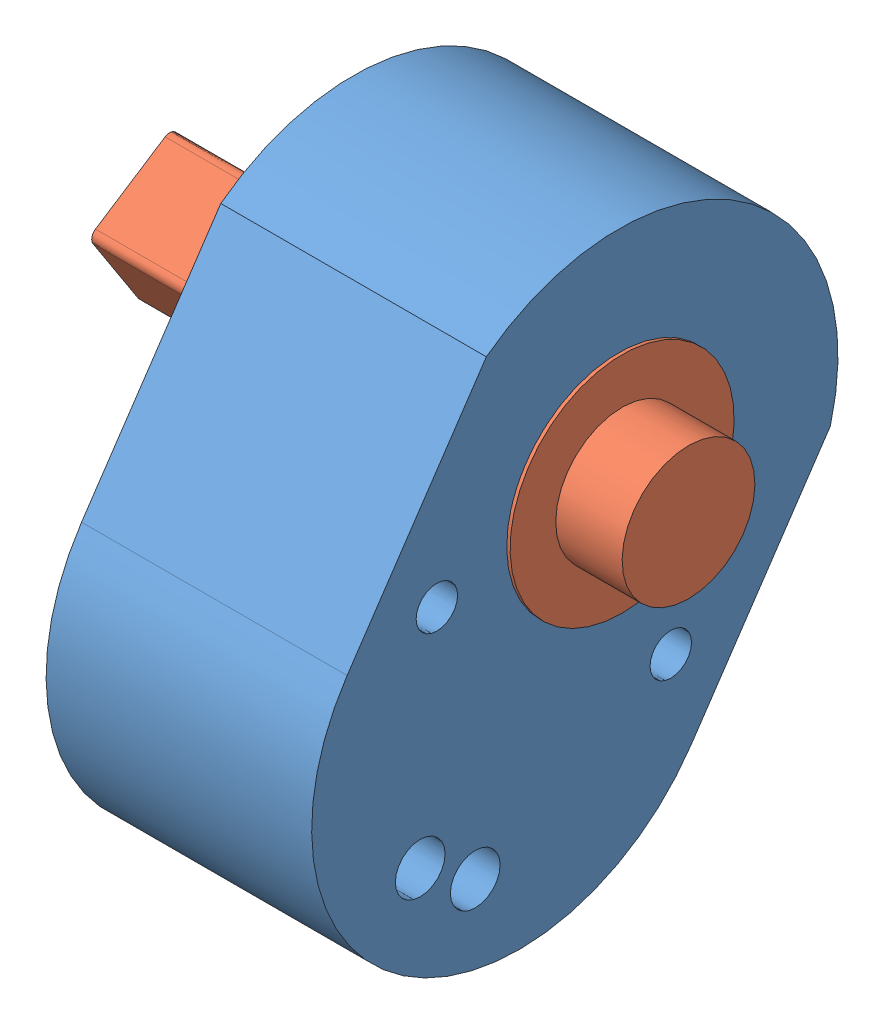
SolidWorks assembly 装配体棘轮, configuration 默认. Lengths in mm.
Overall size (32 34.61 31.71).
6 component instances, 6 part files, 7 mates.
Components (placement in the parent):
- 棘轮-1: 棘轮 [默认] at origin size (16 34.61 31.71)
- 棘轮轮齿-1: 棘轮轮齿 [默认] at (1.5 44.1826 -31.5548) x (0 -0.543538 0.839384) z (0 0.839384 0.543538) size (18.39 32 18.39)
- 棘轮顶片-1: 棘轮顶片 [默认] at (13.5 27.7832 -22.9057) x (0 -0.221935 0.975062) z (-1 0 0) size (11.37 7.28 8)
- 零件2^装配体棘轮-1: 零件2^装配体棘轮 [默认] at origin (virtual)
- 零件3^装配体棘轮-1: 零件3^装配体棘轮 [默认] at origin (virtual)
- 棘轮壳片-1: 棘轮壳片 [默认] at (3.5 44.1826 -31.5548) x (0 0 1) z (0 -1 0) size (27.54 2 29.93)
Mates (geometry in assembly coordinates):
- 同心1: concentric anti-aligned: cylinder of 棘轮-1 through (17.3 44.1826 -31.5548) axis (-1 0 0) radius 6.75; cylinder of 棘轮轮齿-1 through (21.5 44.1826 -31.5548) axis (1 0 0) radius 6.75
- 同心2: concentric anti-aligned: cylinder of 棘轮-1 through (17.3 27.7832 -22.9057) axis (-1 0 0) radius 1.5; cylinder of 棘轮顶片-1 through (5.5 27.7832 -22.9057) axis (1 0 0) radius 1.4
- 重合1: coincident anti-aligned: plane of 棘轮-1 through (13.5 40.5189 -29.0836) normal (-1 0 0); plane of 棘轮顶片-1 through (13.5 27.5773 -25.2969) normal (1 0 0)
- 重合2: coincident anti-aligned: plane of 棘轮-1 through (13.5 40.5189 -29.0836) normal (-1 0 0); plane of 棘轮轮齿-1 through (13.5 40.5138 -25.889) normal (1 0 0)
- 重合3: coincident anti-aligned: plane of 棘轮-1 through (3.5 40.5189 -29.0836) normal (-1 0 0); plane of 棘轮壳片-1 through (3.5 40.5189 -29.0836) normal (1 0 0)
- 同心3: concentric aligned: cylinder of 棘轮轮齿-1 through (21.5 44.1826 -31.5548) axis (1 0 0) radius 6.75; cylinder of 棘轮壳片-1 through (1.5 44.1826 -31.5548) axis (1 0 0) radius 6.75
- 同心4: concentric anti-aligned: cylinder of 棘轮-1 through (17.3 33.6262 -34.6873) axis (-1 0 0) radius 1.25; cylinder of 棘轮壳片-1 through (1.5 33.6262 -34.6873) axis (1 0 0) radius 1.25
